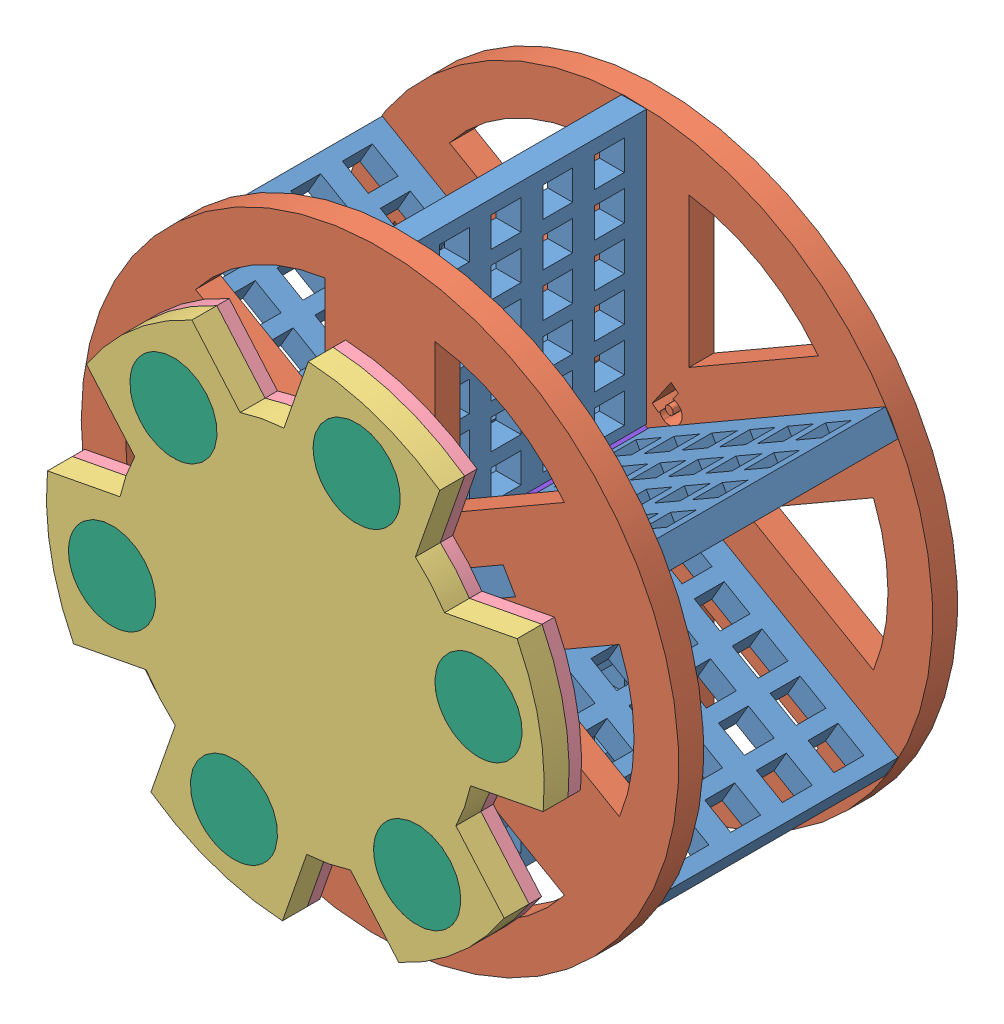
SolidWorks assembly wheel_and_axle, configuration Default. Lengths in mm.
Overall size (76.2 76.2 50.8).
23 component instances, 9 part files, 29 mates.
Components (placement in the parent):
- wheel_spokes-1: wheel_spokes [Default] at (-11.3111 -16.0879 17.7062) size (3.17 34.8 35.56)
- wheel-1: wheel [Default] at (-9.7236 -12.9129 14.5312) size (76.2 76.2 3.17)
- wheel_spokes-2: wheel_spokes [Default] at (-13.267 -13.1256 17.7062) x (0.5 -0.866025 0) z (0 0 1) size (3.17 34.8 35.56)
- wheel_spokes-3: wheel_spokes [Default] at (-11.6795 -9.9506 17.7062) x (-0.5 -0.866025 0) z (0 0 1) size (3.17 34.8 35.56)
- wheel_spokes-4: wheel_spokes [Default] at (-6.1802 -12.7002 17.7062) x (-0.5 0.866025 0) z (0 0 1) size (3.17 34.8 35.56)
- wheel_spokes-5: wheel_spokes [Default] at (-8.1361 -9.7379 17.7062) x (-1 0 0) z (0 0 1) size (3.17 34.8 35.56)
- wheel_spokes-6: wheel_spokes [Default] at (-7.7677 -15.8752 17.7062) x (0.5 0.866025 0) z (0 0 1) size (3.17 34.8 35.56)
- wheel-2: wheel [Default] at (-9.7236 -12.9129 -17.8538) size (76.2 76.2 3.17)
- SLATE_mounts-1: SLATE_mounts [Default] at (-37.5621 0.036 19.4438) x (-0.187192 0.982323 0) z (0 0 -1) size (61.68 63.5 6.35)
  - magnetic_mount_back-1: magnetic_mount_back [Default] at (-17.9312 24.9224 -9.0574) size (61.68 63.5 3.17)
  - magnetic_mount_front-1: magnetic_mount_front [Default] at (-17.9312 24.9224 -5.8824) size (61.68 63.5 3.17)
  - connector-1: connector [Default] at (-17.9312 24.9224 -2.7074) x (-0.5 -0.866025 0) z (0 0 -1) size (38.1 38.1 1.59)
  - n72_magnet-1: n72_magnet [Default] at (2.6713 36.8173 -9.0574) size (11.11 11.11 3.17)
  - n72_magnet-2: n72_magnet [Default] at (-17.9312 48.7122 -9.0574) x (0.5 0.866025 0) z (0 0 1) size (11.11 11.11 3.17)
  - n72_magnet-3: n72_magnet [Default] at (-38.5337 36.8173 -9.0574) x (-0.5 0.866025 0) z (0 0 1) size (11.11 11.11 3.17)
  - n72_magnet-4: n72_magnet [Default] at (-38.5337 13.0276 -9.0574) x (-1 0 0) z (0 0 1) size (11.11 11.11 3.17)
  - n72_magnet-5: n72_magnet [Default] at (-17.9312 1.1327 -9.0574) x (-0.5 -0.866025 0) z (0 0 1) size (11.11 11.11 3.17)
  - n72_magnet-6: n72_magnet [Default] at (2.6713 13.0276 -9.0574) x (0.5 -0.866025 0) z (0 0 1) size (11.11 11.11 3.17)
  - d31_magnet-1: d31_magnet [Default] at (-17.9312 24.9224 -4.2949) x (-0.923728 -0.383049 0) z (0 0 -1) size (4.76 4.76 1.59)
  - d31_magnet-2: d31_magnet [Default] at (-17.9312 24.9224 -2.7074) x (-0.923728 -0.383049 0) z (0 0 -1) size (4.76 4.76 1.59)
- axle-1: axle [Default] at (-9.7236 -12.9129 -22.2988) size (6.6 6.6 44.45)
- endcap-1: endcap [Default] at (-9.7236 -12.9129 -22.2988) x (0.567658 -0.823264 0) z (0 0 1) size (10.16 10.16 3.17)
- endcap-2: endcap [Default] at (-9.7236 -12.9129 18.9762) size (10.16 10.16 3.17)
Mates (geometry in assembly coordinates):
- Coincident1: coincident aligned: plane of wheel_spokes-1 through (-8.1361 -16.0879 17.7062) normal (0 0 1); plane of wheel-1 through (-9.7236 -12.9129 17.7062) normal (0 0 1)
- Coincident2: coincident anti-aligned: plane of wheel_spokes-1 through (-8.1361 25.0601 17.7062) normal (1 0 0); plane of wheel-1 through (-8.1361 -96.8743 14.5312) normal (-1 0 0)
- Coincident3: coincident anti-aligned: plane of wheel_spokes-1 through (-11.3111 -0.2129 14.5312) normal (0 -1 0); plane of wheel-1 through (-9.7236 -0.2129 14.5312) normal (0 1 0)
- Coincident4: coincident aligned: plane of wheel-1 through (-9.7236 -12.9129 17.7062) normal (0 0 1); plane of wheel_spokes-2 through (-11.6795 -15.8752 17.7062) normal (0 0 1)
- Coincident5: coincident anti-aligned: plane of wheel-1 through (43.1305 -66.359 14.5312) normal (-0.866025 -0.5 0); plane of wheel_spokes-2 through (5.9804 -2.0131 14.5312) normal (0.866025 0.5 0)
- Coincident6: coincident anti-aligned: plane of wheel-1 through (-46.8737 -32.5285 14.5312) normal (0.5 -0.866025 0); plane of wheel_spokes-2 through (22.3682 7.4484 17.7062) normal (-0.5 0.866025 0)
- Coincident7: coincident aligned: plane of wheel-1 through (-9.7236 -12.9129 17.7062) normal (0 0 1); plane of wheel_spokes-3 through (-13.267 -12.7002 17.7062) normal (0 0 1)
- Coincident8: coincident anti-aligned: plane of wheel-1 through (-29.5822 -85.409 14.5312) normal (-0.866025 0.5 0); plane of wheel_spokes-3 through (7.5679 -21.0631 14.5312) normal (0.866025 -0.5 0)
- Coincident9: coincident anti-aligned: plane of wheel-1 through (25.839 -35.2781 14.5312) normal (0.5 0.866025 0); plane of wheel_spokes-3 through (22.3682 -33.2742 17.7062) normal (-0.5 -0.866025 0)
- Coincident10: coincident aligned: plane of wheel-1 through (-9.7236 -12.9129 17.7062) normal (0 0 1); plane of wheel_spokes-5 through (-11.3111 -9.7379 17.7062) normal (0 0 1)
- Coincident11: coincident anti-aligned: plane of wheel-1 through (-9.7236 -31.9629 14.5312) normal (0 1 0); plane of wheel_spokes-5 through (-8.1361 -31.9629 14.5312) normal (0 -1 0)
- Coincident12: coincident anti-aligned: plane of wheel-1 through (-8.1361 -96.8743 14.5312) normal (-1 0 0); plane of wheel_spokes-5 through (-8.1361 -50.8859 17.7062) normal (1 0 0)
- Coincident13: coincident aligned: plane of wheel-1 through (-9.7236 -12.9129 17.7062) normal (0 0 1); plane of wheel_spokes-4 through (-7.7677 -9.9506 17.7062) normal (0 0 1)
- Coincident14: coincident aligned: plane of wheel-1 through (-9.7236 -12.9129 17.7062) normal (0 0 1); plane of wheel_spokes-4 through (-7.7677 -9.9506 17.7062) normal (0 0 1)
- Coincident15: coincident anti-aligned: plane of wheel-1 through (10.135 -85.409 14.5312) normal (0.866025 0.5 0); plane of wheel_spokes-4 through (-25.4276 -23.8127 14.5312) normal (-0.866025 -0.5 0)
- Coincident16: coincident anti-aligned: plane of wheel-1 through (-46.8737 -32.5285 14.5312) normal (0.5 -0.866025 0); plane of wheel_spokes-4 through (-43.4029 -30.5246 17.7062) normal (-0.5 0.866025 0)
- Coincident17: coincident aligned: plane of wheel-1 through (-9.7236 -12.9129 17.7062) normal (0 0 1); plane of wheel_spokes-6 through (-6.1802 -13.1256 17.7062) normal (0 0 1)
- Coincident18: coincident anti-aligned: plane of wheel-1 through (25.839 -35.2781 14.5312) normal (0.5 0.866025 0); plane of wheel_spokes-6 through (-43.4029 4.6988 17.7062) normal (-0.5 -0.866025 0)
- Coincident19: coincident anti-aligned: plane of wheel-1 through (-62.5777 -66.359 14.5312) normal (0.866025 -0.5 0); plane of wheel_spokes-6 through (-27.0151 -4.7627 14.5312) normal (-0.866025 0.5 0)
- Coincident20: coincident anti-aligned: plane of wheel-2 through (-9.7236 -12.9129 -14.6788) normal (0 0 1); plane of wheel_spokes-2 through (22.3682 7.4484 -14.6788) normal (0 0 -1)
- Coincident21: coincident anti-aligned: plane of wheel_spokes-6 through (-27.0151 -4.7627 -14.6788) normal (-0.866025 0.5 0); plane of wheel-2 through (-62.5777 -66.359 -17.8538) normal (0.866025 -0.5 0)
- Coincident22: coincident anti-aligned: plane of wheel_spokes-6 through (-41.8154 7.4484 17.7062) normal (0.5 0.866025 0); plane of wheel-2 through (27.4265 -32.5285 -17.8538) normal (-0.5 -0.866025 0)
- Concentric2: concentric anti-aligned: cylinder of wheel-2 through (-9.7236 -12.9129 -17.8538) axis (0 0 1) radius 3.302; cylinder of axle-1 through (-9.7236 -12.9129 22.1512) axis (0 0 -1) radius 3.302
- Concentric3: concentric aligned: cylinder of axle-1 through (-9.7236 -12.9129 22.1512) axis (0 0 -1) radius 3.302; cylinder of endcap-1 through (-9.7236 -12.9129 -19.1238) axis (0 0 -1) radius 3.302
- Coincident26: coincident aligned: plane of axle-1 through (-9.7236 -12.9129 -22.2988) normal (0 0 -1); plane of endcap-1 through (-9.7236 -12.9129 -22.2988) normal (0 0 -1)
- Concentric4: concentric aligned: circle of SLATE_mounts-1/d31_magnet-2; circle of axle-1
- Coincident27: coincident anti-aligned: plane of SLATE_mounts-1/connector-1 through (-9.7236 -12.9129 22.1512) normal (0 0 -1); plane of axle-1 through (-9.7236 -12.9129 22.1512) normal (0 0 1)
- Concentric5: concentric aligned: cylinder of axle-1 through (-9.7236 -12.9129 22.1512) axis (0 0 -1) radius 3.302; cylinder of endcap-2 through (-9.7236 -12.9129 22.1512) axis (0 0 -1) radius 3.302
- Coincident28: coincident anti-aligned: plane of SLATE_mounts-1/connector-1 through (-9.7236 -12.9129 22.1512) normal (0 0 -1); plane of endcap-2 through (-9.7236 -12.9129 22.1512) normal (0 0 1)
